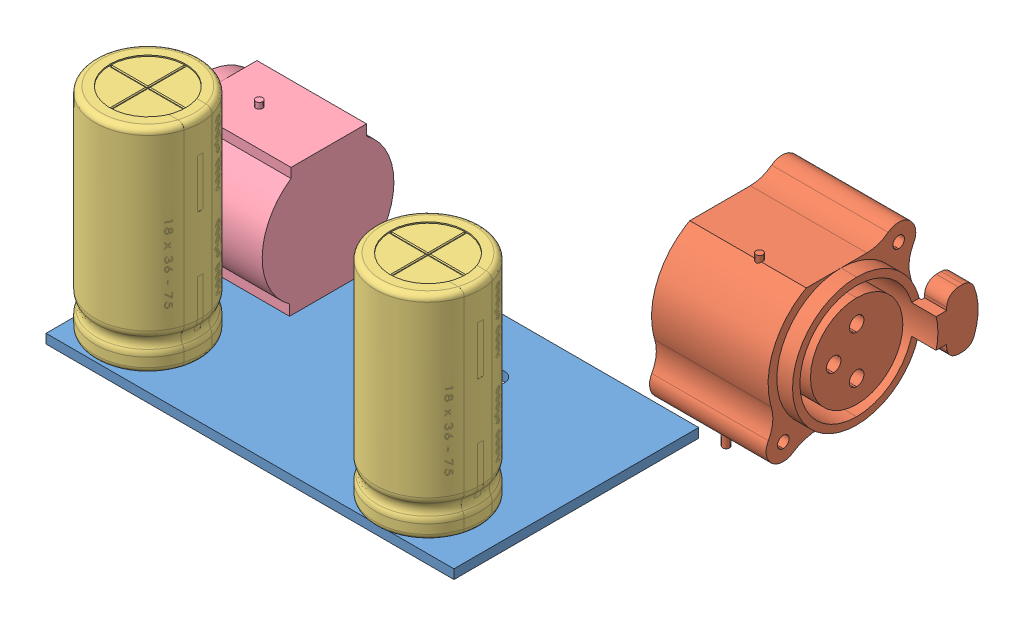
SolidWorks assembly PCB-asm, configuration Default. Lengths in mm.
Overall size (90.52 40.56 73.82).
5 component instances, 4 part files, 7 mates.
Components (placement in the parent):
- PCB-1: PCB [Default] at origin size (70 1.6 42)
- d-nc3fahr2.stp-1: d-nc3fahr2.stp [Default] at (45.4956 12.6 -34.9075) x (0 1 0) z (-1 0 0) size (27.35 29.5 26.9)
- Cap-EL18x36-7_5T-1: Cap-EL18x36-7_5T [Varsayılan] at (22.806 1.6 13.2598) x (1 0 0) z (0 1 0) size (18.1 18 40.06)
- Cap-EL18x36-7_5T-2: Cap-EL18x36-7_5T [Varsayılan] at (-26.0182 1.6 12.5085) x (1 0 0) z (0 1 0) size (18.1 18 40.06)
- nc3mahl-1.stp-1: nc3mahl-1.stp [Default] at (-35.4282 12.6 -9.0262) x (0 -1 0) z (1 0 0) size (27.3 25.6 21.5)
Mates (geometry in assembly coordinates):
- Coincident1: coordinate: point of PCB-1
- Coincident3: coincident anti-aligned: plane of PCB-1 through (0 1.6 0) normal (0 1 0); plane of d-nc3fahr2.stp-1 through (45.4956 1.6 -40.8446) normal (0 -1 0)
- Coincident4: coincident anti-aligned: plane of PCB-1 through (0 1.6 0) normal (0 1 0); plane of nc3mahl-1.stp-1 through (-35.4282 1.6 -2.4262) normal (0 -1 0)
- Parallel1: parallel aligned: plane of PCB-1 through (35 1.6 21) normal (1 0 0); plane of d-nc3fahr2.stp-1 through (48.1956 12.6 -34.9075) normal (1 0 0)
- Parallel2: parallel aligned: plane of PCB-1 through (-35 1.6 21) normal (-1 0 0); plane of nc3mahl-1.stp-1 through (-38.1282 12.6 -9.0262) normal (-1 0 0)
- Coincident5: coincident anti-aligned: plane of PCB-1 through (0 1.6 0) normal (0 1 0); plane of Cap-EL18x36-7_5T-2 through (-26.0182 1.6 12.5085) normal (0 -1 0)
- Coincident6: coincident anti-aligned: plane of PCB-1 through (0 1.6 0) normal (0 1 0); plane of Cap-EL18x36-7_5T-1 through (22.806 1.6 13.2598) normal (0 -1 0)
